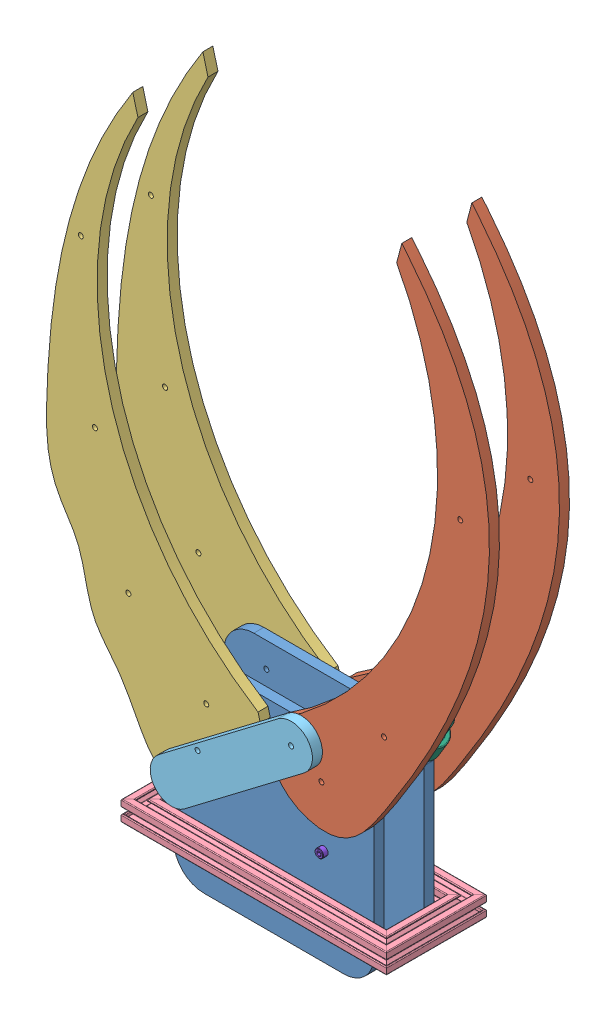
SolidWorks assembly claw complete, configuration Default. Lengths in mm.
12 component instances, 8 part files, 24 mates.
Components (placement in the parent):
- base (1)-1: base (1) [Default] at (84.5945 78.7634 160.6694) size (200 200 10)
- left-1: left [Default] at (97.6438 176.1538 100.6694) x (0.967017 -0.254711 0) z (0 0 1) size (196.08 572.16 10)
- right-1: right [Default] at (78.7753 172.5806 100.6694) x (0.966864 0.255292 0) z (0 0 1) size (173.08 567.26 10)
- base (1)-2: base (1) [Default] at (84.5945 78.7634 110.6694) size (200 200 10)
- right-2: right [Default] at (78.7753 172.5806 170.6694) x (0.966864 0.255292 0) z (0 0 1) size (173.08 567.26 10)
- left-2: left [Default] at (97.6438 176.1538 170.6694) x (0.967017 -0.254711 0) z (0 0 1) size (196.08 572.16 10)
- claw support-3: claw support [Default<As Machined>] at (84.5945 28.7634 140.6694) x (-1 0 0) z (0 1 0) size (265 100 20)
- claw motion-1: claw motion [Default] at (64.7629 126.4273 180.6694) x (0.79619 0.605047 0) z (0 0 1) size (192.73 42.73 10)
- cylinder assembly-1: cylinder assembly [Default] at (148.8168 100.0117 48.5018) x (0 0 -1) z (0.516333 0.856388 0) size (30 32.55 195)
  - cylinder-1: cylinder [Default] at (-92.1798 -0.5475 141.514) size (30 32.55 185)
  - cylinder rod-1: cylinder rod [Default] at (-92.1798 -0.5475 51.514) x (0.995961 0.089791 0) z (0.089791 -0.995961 0) size (10 100 10)
- socket head cap screw_am-1: socket head cap screw_am [PreviewCfg] at (134.5775 75.334 175.6694) x (0 0 -1) z (0.998896 -0.046986 0) size (29 7 7)
Mates (geometry in assembly coordinates):
- Distance3: distance = 40 mm aligned: plane of claw support-3 through (-37.9055 18.7634 184.4694) normal (0 -1 0); plane of base (1)-2 through (14.5945 -21.2366 120.6694) normal (0 -1 0)
- Concentric17: concentric aligned: cylinder of left-2 through (121.8192 169.786 180.6694) axis (0 0 -1) radius 2.5; cylinder of claw motion-1 through (121.8192 169.786 190.6694) axis (0 0 -1) radius 2.5
- Concentric18: concentric aligned: cylinder of right-2 through (28.4116 119.0557 180.6694) axis (0 0 -1) radius 2.5; cylinder of claw motion-1 through (28.4116 119.0557 190.6694) axis (0 0 -1) radius 2.5
- Coincident13: coincident anti-aligned: plane of right-2 through (262.9987 464.277 180.6694) normal (0 0 1); plane of claw motion-1 through (2.3907 79.029 180.6694) normal (0 0 -1)
- Coincident14: coincident anti-aligned: plane of left-2 through (289.7572 315.3858 180.6694) normal (0 0 1); plane of claw motion-1 through (2.3907 79.029 180.6694) normal (0 0 -1)
- Coincident15: coincident anti-aligned: plane of base (1)-1 through (14.5945 8.7634 170.6694) normal (0 0 1); plane of claw support-3 through (-37.9055 24.9634 170.6694) normal (0 0 -1)
- Coincident20: coincident anti-aligned: plane of base (1)-1 through (14.5945 8.7634 170.6694) normal (0 0 1); plane of left-2 through (289.7572 315.3858 170.6694) normal (0 0 -1)
- Concentric19: concentric aligned: cylinder of base (1)-1 through (142.0945 143.7634 170.6694) axis (0 0 -1) radius 2.5; cylinder of left-2 through (142.0945 143.7634 180.6694) axis (0 0 -1) radius 2.5
- Concentric20: concentric aligned: cylinder of base (1)-1 through (27.0945 153.7634 170.6694) axis (0 0 -1) radius 2.5; cylinder of right-2 through (27.0945 153.7634 180.6694) axis (0 0 -1) radius 2.5
- Concentric21: concentric aligned: cylinder of right-1 through (-50.7146 210.5898 110.6694) axis (0 0 -1) radius 2.5; cylinder of right-2 through (-50.7146 210.5898 180.6694) axis (0 0 -1) radius 2.5
- Concentric22: concentric aligned: cylinder of right-1 through (-84.1373 337.1715 110.6694) axis (0 0 -1) radius 2.5; cylinder of right-2 through (-84.1373 337.1715 180.6694) axis (0 0 -1) radius 2.5
- Concentric23: concentric aligned: cylinder of left-1 through (280.8661 439.9001 110.6694) axis (0 0 -1) radius 2.5; cylinder of left-2 through (280.8661 439.9001 180.6694) axis (0 0 -1) radius 2.5
- Concentric24: concentric aligned: cylinder of left-1 through (142.0945 143.7634 110.6694) axis (0 0 -1) radius 2.5; cylinder of base (1)-2 through (142.0945 143.7634 120.6694) axis (0 0 -1) radius 2.5
- Coincident23: coincident anti-aligned: plane of base (1)-2 through (14.5945 8.7634 110.6694) normal (0 0 -1); plane of claw support-3 through (-37.9055 37.9634 110.6694) normal (0 0 1)
- Width1: width anti-aligned: plane of claw support-3 through (197.0945 24.9634 180.6694) normal (-1 0 0); plane of claw support-3 through (-27.9055 24.9634 180.6694) normal (1 0 0); plane of base (1)-1 through (184.5945 8.7634 170.6694) normal (1 0 0); plane of base (1)-1 through (-15.4055 8.7634 170.6694) normal (-1 0 0)
- Concentric25: concentric aligned: cylinder of base (1)-1 through (134.5775 75.334 170.6694) axis (0 0 -1) radius 4; cylinder of base (1)-2 through (134.5775 75.334 120.6694) axis (0 0 -1) radius 4
- Concentric26: concentric aligned: cylinder of base (1)-1 through (134.5775 75.334 170.6694) axis (0 0 -1) radius 4; cylinder of cylinder assembly-1/cylinder-1 through (134.5775 75.334 155.6816) axis (0 0 -1) radius 4
- Width2: width aligned: plane of cylinder assembly-1/cylinder-1 through (134.5775 75.334 148.1816) normal (0 0 1); plane of cylinder assembly-1/cylinder-1 through (134.5775 75.334 133.1572) normal (0 0 -1); plane of base (1)-2 through (14.5945 8.7634 120.6694) normal (0 0 1); plane of base (1)-1 through (14.5945 8.7634 160.6694) normal (0 0 -1)
- Coincident24: coincident anti-aligned: plane of right-1 through (262.9987 464.277 110.6694) normal (0 0 1); plane of base (1)-2 through (14.5945 8.7634 110.6694) normal (0 0 -1)
- Coincident25: coincident anti-aligned: plane of left-1 through (289.7572 315.3858 110.6694) normal (0 0 1); plane of base (1)-2 through (14.5945 8.7634 110.6694) normal (0 0 -1)
- Concentric27: concentric anti-aligned: cylinder of base (1)-1 through (134.5775 75.334 170.6694) axis (0 0 -1) radius 4; cylinder of socket head cap screw_am-1 through (134.5775 75.334 207.4194) axis (0 0 1) radius 4.25
- Coincident26: coincident anti-aligned: plane of base (1)-1 through (14.5945 8.7634 170.6694) normal (0 0 1); plane of socket head cap screw_am-1 through (134.7772 79.5793 170.6694) normal (0 0 -1)
- Lock1: lock: unknown of cylinder assembly-1/cylinder-1; unknown of socket head cap screw_am-1
- Lock2: lock: unknown of base (1)-1; unknown of cylinder assembly-1/cylinder-1
